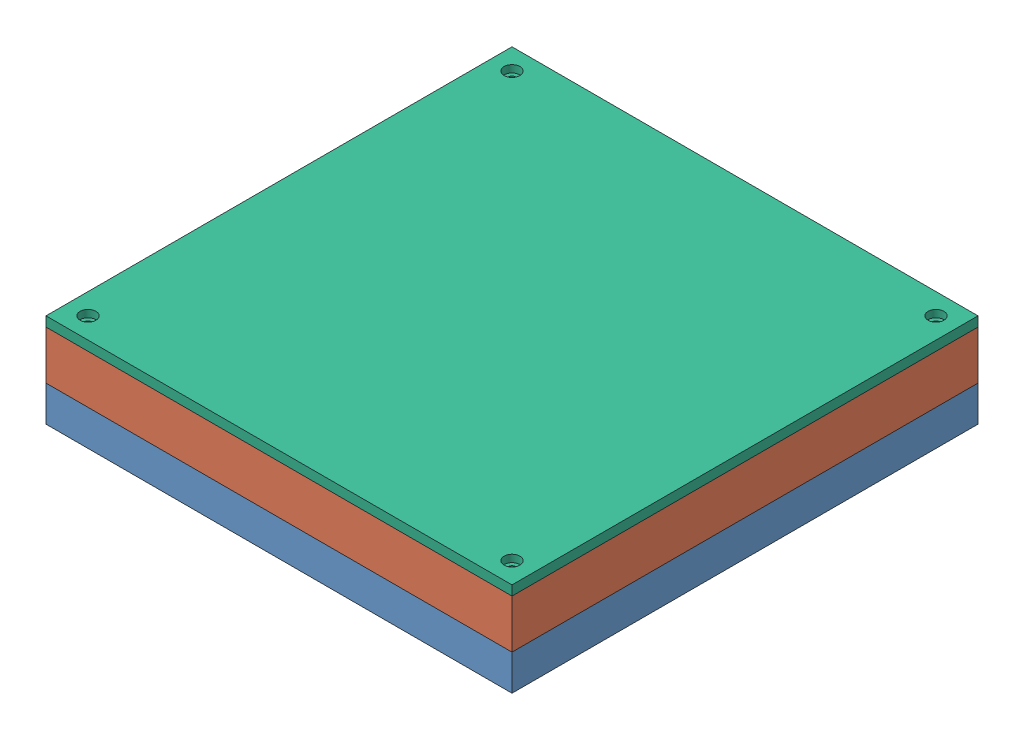
SolidWorks assembly MountAssembly, configuration Default. Lengths in mm.
Overall size (192 38.66 192).
13 component instances, 6 part files, 31 mates.
Components (placement in the parent):
- LED Matrix 64x64-1: LED Matrix 64x64 [Default] at (1.767 -32.7909 16.3654) size (192 15.66 192)
- PanelMount-1: PanelMount [Default] at (1.767 -18.1309 16.3654) x (1 0 0) z (0 1 0) size (192 192 20)
- socket head cap screw_am-1: socket head cap screw_am [B18.3.1M - 3 x 0.5 x 12 Hex SHCS -- 12NHX] at (86.467 1.8691 -56.9846) x (0 -1 0) z (0 0 1) size (15 5.5 5.5)
- socket head cap screw_am-2: socket head cap screw_am [B18.3.1M - 3 x 0.5 x 12 Hex SHCS -- 12NHX] at (-82.933 1.8691 -56.9846) x (0 -1 0) z (0 0 1) size (15 5.5 5.5)
- socket head cap screw_am-3: socket head cap screw_am [B18.3.1M - 3 x 0.5 x 12 Hex SHCS -- 12NHX] at (-82.933 1.8691 89.7154) x (0 -1 0) z (0 0 1) size (15 5.5 5.5)
- socket head cap screw_am-4: socket head cap screw_am [B18.3.1M - 3 x 0.5 x 12 Hex SHCS -- 12NHX] at (86.467 1.8691 89.7154) x (0 -1 0) z (0 0 1) size (15 5.5 5.5)
- ST1 Stripboard-1: ST1 Stripboard [Default] at (-33.933 -12.1309 -34.3346) size (80 1.6 50)
- socket head cap screw_am-5: socket head cap screw_am [B18.3.1M - 3 x 0.5 x 8 Hex SHCS -- 8NHX] at (1.627 -7.5309 -14.0146) x (0 -1 0) z (0 0 1) size (11 5.5 5.5)
- socket head cap screw_am-6: socket head cap screw_am [B18.3.1M - 3 x 0.5 x 8 Hex SHCS -- 8NHX] at (-69.493 -7.5309 -14.0146) x (0 -1 0) z (0 0 1) size (11 5.5 5.5)
- socket head cap screw_am-7: socket head cap screw_am [B18.3.1M - 3 x 0.5 x 8 Hex SHCS -- 8NHX] at (1.627 -7.5309 -54.6546) x (0 -1 0) z (0 0 1) size (11 5.5 5.5)
- socket head cap screw_am-8: socket head cap screw_am [B18.3.1M - 3 x 0.5 x 8 Hex SHCS -- 8NHX] at (-69.493 -7.5309 -54.6546) x (0 -1 0) z (0 0 1) size (11 5.5 5.5)
- DC Jack-1: DC Jack [Default] at (71.017 -8.1309 -67.4346) x (0 -1 0) z (1 0 0) size (11 18.2 12.7)
- MountCover-1: MountCover [Default] at (1.767 1.8691 16.3654) x (1 0 0) z (0 1 0) size (192 192 4)
Mates (geometry in assembly coordinates):
- InPlace1: in place: plane of LED Matrix 64x64-1 through (1.767 -18.1309 16.3654) normal (0 1 0); plane of ? through (0 -18.1309 0) normal (0 1 0); moOrthogonalPlaneRef_w of LED Matrix 64x64-1 through (1.767 -18.1309 16.3654) normal (0 1 0); plane of ? through (0 -18.1309 0) normal (0 0 -1); plane of LED Matrix 64x64-1 through (1.767 -18.1309 16.3654) normal (0 1 0); plane of ? through (0 -18.1309 0) normal (1 0 0); plane of LED Matrix 64x64-1 through (1.767 -18.1309 16.3654) normal (0 1 0); unknown of PanelMount-1
- Coincident1: coincident aligned: plane of ?; plane of ?
- Coincident2: coincident aligned: moOrthogonalPlaneRef_w of LED Matrix 64x64-1 through (1.767 -18.1309 16.3654) normal (0 0 -1); plane of Part6^MountAssembly-1 through (1.767 -18.1309 16.3654) normal (0 0 -1)
- Coincident3: coincident anti-aligned: moOrthogonalPlaneRef_w of LED Matrix 64x64-1 through (1.767 -18.1309 16.3654) normal (-1 0 0); plane of Part6^MountAssembly-1 through (1.767 -18.1309 16.3654) normal (1 0 0)
- Concentric1: concentric aligned: cylinder of PanelMount-1 through (86.467 1.8691 -56.9846) axis (0 1 0) radius 1.7; cylinder of socket head cap screw_am-1 through (86.467 33.6191 -56.9846) axis (0 1 0) radius 2.75
- Coincident4: coincident anti-aligned: plane of PanelMount-1 through (88.167 -1.1309 -56.9846) normal (0 1 0); plane of socket head cap screw_am-1 through (89.217 -1.1309 -56.9846) normal (0 -1 0)
- Concentric2: concentric aligned: cylinder of PanelMount-1 through (-82.933 1.8691 -56.9846) axis (0 1 0) radius 1.7; cylinder of socket head cap screw_am-2 through (-82.933 33.6191 -56.9846) axis (0 1 0) radius 2.75
- Coincident5: coincident anti-aligned: plane of PanelMount-1 through (-81.233 -1.1309 -56.9846) normal (0 1 0); plane of socket head cap screw_am-2 through (-80.183 -1.1309 -56.9846) normal (0 -1 0)
- Concentric3: concentric aligned: cylinder of PanelMount-1 through (-82.933 1.8691 89.7154) axis (0 1 0) radius 1.7; cylinder of socket head cap screw_am-3 through (-82.933 33.6191 89.7154) axis (0 1 0) radius 2.75
- Coincident6: coincident anti-aligned: plane of PanelMount-1 through (-81.233 -1.1309 89.7154) normal (0 1 0); plane of socket head cap screw_am-3 through (-80.183 -1.1309 89.7154) normal (0 -1 0)
- Concentric4: concentric aligned: cylinder of PanelMount-1 through (86.467 1.8691 89.7154) axis (0 1 0) radius 1.7; cylinder of socket head cap screw_am-4 through (86.467 33.6191 89.7154) axis (0 1 0) radius 2.75
- Coincident7: coincident anti-aligned: plane of PanelMount-1 through (88.167 -1.1309 89.7154) normal (0 1 0); plane of socket head cap screw_am-4 through (89.217 -1.1309 89.7154) normal (0 -1 0)
- Distance1: distance = 3 mm anti-aligned: plane of ST1 Stripboard-1 through (-73.933 -10.5309 -59.3346) normal (0 0 -1); plane of PanelMount-1 through (-76.933 1.8691 -62.3346) normal (0 0 1)
- Distance2: distance = 3 mm anti-aligned: plane of PanelMount-1 through (-76.933 1.8691 -62.3346) normal (1 0 0); plane of ST1 Stripboard-1 through (-73.933 -10.5309 -9.3346) normal (-1 0 0)
- Distance3: distance = 2 mm anti-aligned: plane of ST1 Stripboard-1 through (-33.933 -12.1309 -34.3346) normal (0 -1 0); plane of PanelMount-1 through (1.767 -14.1309 16.3654) normal (0 1 0)
- Concentric5: concentric aligned: cylinder of ST1 Stripboard-1 through (1.627 -10.5309 -14.0146) axis (0 1 0) radius 1.5875; cylinder of socket head cap screw_am-5 through (1.627 24.2191 -14.0146) axis (0 1 0) radius 2.75
- Coincident9: coincident anti-aligned: plane of ST1 Stripboard-1 through (-33.933 -10.5309 -34.3346) normal (0 1 0); plane of socket head cap screw_am-5 through (4.377 -10.5309 -14.0146) normal (0 -1 0)
- Concentric6: concentric aligned: cylinder of ST1 Stripboard-1 through (-69.493 -10.5309 -14.0146) axis (0 1 0) radius 1.5875; cylinder of socket head cap screw_am-6 through (-69.493 24.2191 -14.0146) axis (0 1 0) radius 2.75
- Coincident10: coincident anti-aligned: plane of ST1 Stripboard-1 through (-33.933 -10.5309 -34.3346) normal (0 1 0); plane of socket head cap screw_am-6 through (-66.743 -10.5309 -14.0146) normal (0 -1 0)
- Concentric7: concentric aligned: cylinder of ST1 Stripboard-1 through (1.627 -10.5309 -54.6546) axis (0 1 0) radius 1.5875; cylinder of socket head cap screw_am-7 through (1.627 24.2191 -54.6546) axis (0 1 0) radius 2.75
- Coincident11: coincident anti-aligned: plane of ST1 Stripboard-1 through (-33.933 -10.5309 -34.3346) normal (0 1 0); plane of socket head cap screw_am-7 through (4.377 -10.5309 -54.6546) normal (0 -1 0)
- Concentric8: concentric aligned: cylinder of ST1 Stripboard-1 through (-69.493 -10.5309 -54.6546) axis (0 1 0) radius 1.5875; cylinder of socket head cap screw_am-8 through (-69.493 24.2191 -54.6546) axis (0 1 0) radius 2.75
- Coincident12: coincident anti-aligned: plane of ST1 Stripboard-1 through (-33.933 -10.5309 -34.3346) normal (0 1 0); plane of socket head cap screw_am-8 through (-66.743 -10.5309 -54.6546) normal (0 -1 0)
- Coincident13: coincident aligned: plane of PanelMount-1 through (-94.233 1.8691 -79.6346) normal (0 0 -1); plane of DC Jack-1 through (71.017 -12.6309 -79.6346) normal (0 0 -1)
- Parallel1: parallel aligned: plane of PanelMount-1 through (1.767 1.8691 16.3654) normal (0 1 0); plane of DC Jack-1 through (74.1924 -2.6309 -70.0346) normal (0 1 0)
- Width1: width anti-aligned: plane of DC Jack-1 through (74.1924 -2.6309 -70.0346) normal (0 1 0); plane of PanelMount-1 through (67.8415 -13.6309 -70.0346) normal (0 -1 0); plane of DC Jack-1 through (1.767 -18.1309 16.3654) normal (0 -1 0); plane of PanelMount-1 through (1.767 1.8691 16.3654) normal (0 1 0)
- Distance4: distance = 30 mm anti-aligned: plane of DC Jack-1 through (67.767 -13.1309 -89.6768) normal (-1 0 0); plane of PanelMount-1 through (97.767 1.8691 -79.6346) normal (1 0 0)
- InPlace2: in place: plane of PanelMount-1 through (1.767 1.8691 16.3654) normal (0 1 0); plane of ? through (0 1.8691 0) normal (0 1 0); plane of PanelMount-1 through (1.767 1.8691 16.3654) normal (0 1 0); plane of ? through (0 1.8691 0) normal (0 0 -1); plane of PanelMount-1 through (1.767 1.8691 16.3654) normal (0 1 0); plane of ? through (0 1.8691 0) normal (1 0 0); plane of PanelMount-1 through (1.767 1.8691 16.3654) normal (0 1 0); unknown of MountCover-1
- Coincident14: coincident aligned: plane of ?; plane of ?
- Coincident15: coincident aligned: moOrthogonalPlaneRef_w of PanelMount-1 through (1.767 1.8691 16.3654) normal (0 0 -1); plane of Part7^MountAssembly-1 through (1.767 1.8691 16.3654) normal (0 0 -1)
- Coincident16: coincident anti-aligned: moOrthogonalPlaneRef_w of PanelMount-1 through (1.767 1.8691 16.3654) normal (-1 0 0); plane of Part7^MountAssembly-1 through (1.767 1.8691 16.3654) normal (1 0 0)
